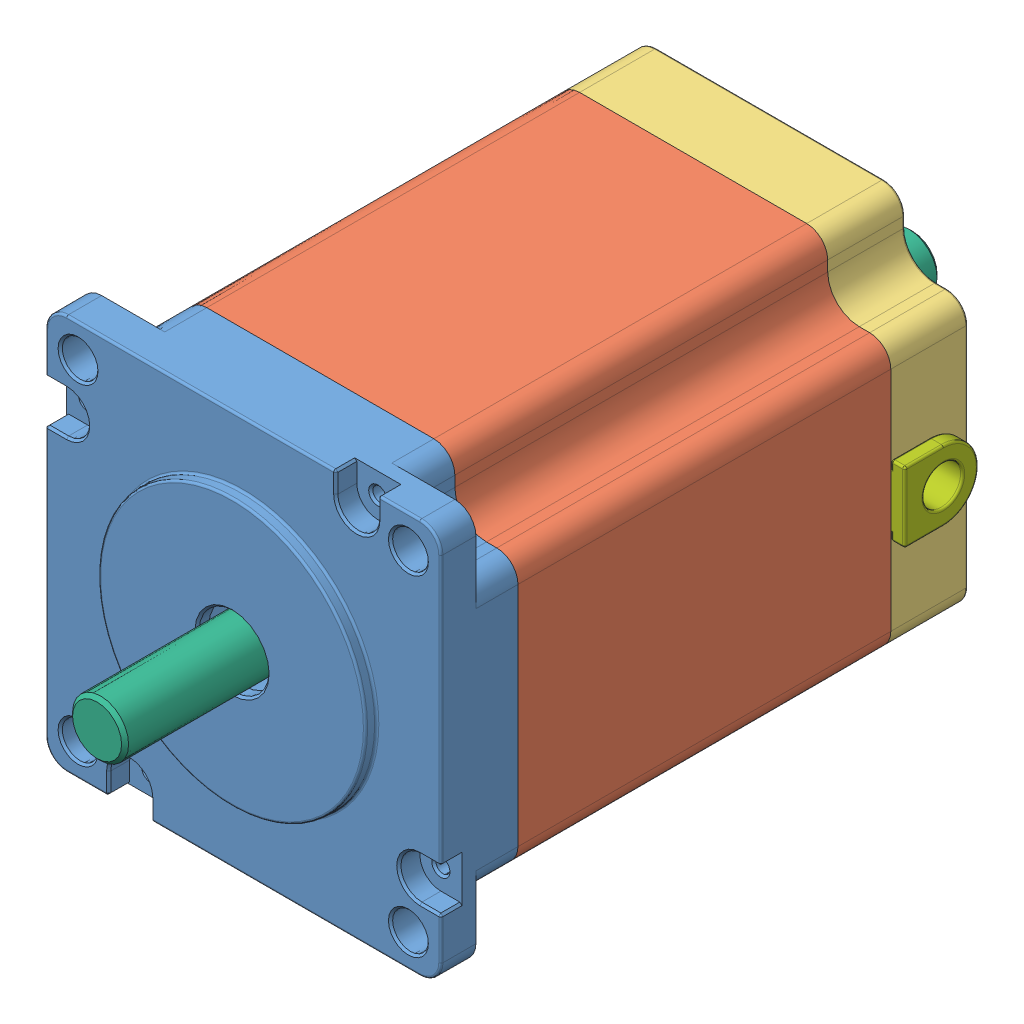
SolidWorks assembly Nema 23 Stepper Motor 57BYGH311D-12, configuration Default. Lengths in mm.
Overall size (58.4 56.4 135.95).
8 component instances, 8 part files, 16 mates.
Components (placement in the parent):
- 57BYGH311D-12-1-1: 57BYGH311D-12-1 [Default] at (-11.5747 12.4138 -2.3259) size (56.4 56.4 14.6)
- 57BYGH311D-12-2-1: 57BYGH311D-12-2 [Default] at (-11.5747 12.4138 -55.5259) size (56.4 56.4 53.2)
- 57BYGH311D-12-3-1: 57BYGH311D-12-3 [Default] at (-11.5747 12.4138 -55.5259) x (-1 0 0) z (0 0 -1) size (56.4 56.4 11)
- 57BYGH311D-12-4-2: 57BYGH311D-12-4 [Default] at (-11.5747 12.4138 -70.0259) size (36 36 15.4)
- 57BYGH311D-12-5-1: 57BYGH311D-12-5 [Default] at (-11.5747 12.4138 -70.5259) x (0.622515 0.782608 0) z (0 0 1) size (35.3 35.21 5)
- 57BYGH311D-12-6-1: 57BYGH311D-12-6 [Default] at (-11.5747 12.4138 -86.8259) size (8 8 116.35)
- 57BYGH311D-12-7-1: 57BYGH311D-12-7 [Default] at (15.4253 12.4138 -61.0259) x (1 0 0) z (0 1 0) size (6.2 10.5 12)
- coupler-1: coupler [Default] at (-11.5747 12.4138 19.5241) x (-0.005303 -0.999986 0) z (-0.999986 0.005303 0) size (26 29.6 26)
Mates (geometry in assembly coordinates):
- Coincident1: coincident: plane of 57BYGH311D-12-1-1 through (13.6253 37.6138 -2.3259) normal (0 0 -1); plane of 57BYGH311D-12-2-1 through (-35.2747 36.1138 -2.3259) normal (0 0 1)
- Coincident2: coincident: plane of 57BYGH311D-12-1-1 through (-36.7747 40.6138 8.6741) normal (0 1 0); plane of 57BYGH311D-12-2-1 through (4.6253 40.6138 -2.3259) normal (0 1 0)
- Coincident3: coincident: plane of 57BYGH311D-12-1-1 through (16.6253 37.6138 8.6741) normal (1 0 0); plane of 57BYGH311D-12-2-1 through (16.6253 28.6138 -2.3259) normal (1 0 0)
- Concentric1: concentric: cylinder of assembly; cylinder of assembly; cylinder of 57BYGH311D-12-3-1 through (-11.5747 12.4138 -65.5259) axis (0 0 1) radius 18; cylinder of 57BYGH311D-12-4-2 through (-11.5747 12.4138 -70.0259) axis (0 0 -1) radius 18
- Coincident4: coincident: plane of assembly; plane of assembly; plane of 57BYGH311D-12-3-1 through (-11.5747 12.4138 -65.5259) normal (0 0 1); plane of 57BYGH311D-12-4-2 through (-29.5747 12.4138 -65.5259) normal (0 0 -1)
- Coincident5: coincident: plane of assembly; plane of assembly; plane of 57BYGH311D-12-2-1 through (-35.2747 36.1138 -55.5259) normal (0 0 -1); plane of 57BYGH311D-12-3-1 through (12.1253 36.1138 -55.5259) normal (0 0 1)
- Coincident6: coincident: plane of assembly; plane of assembly; plane of 57BYGH311D-12-2-1 through (16.6253 28.6138 -2.3259) normal (1 0 0); plane of 57BYGH311D-12-3-1 through (16.6253 -3.7862 -66.5259) normal (1 0 0)
- Coincident7: coincident: plane of assembly; plane of assembly; plane of 57BYGH311D-12-2-1 through (4.6253 40.6138 -2.3259) normal (0 1 0); plane of 57BYGH311D-12-3-1 through (-27.7747 40.6138 -66.5259) normal (0 1 0)
- Coincident8: coincident: plane of assembly; plane of assembly; plane of 57BYGH311D-12-4-2 through (-29.5747 12.4138 -65.5259) normal (0 0 -1); plane of 57BYGH311D-12-5-1 through (-11.5747 12.4138 -65.5259) normal (0 0 1)
- Concentric2: concentric: cylinder of assembly; cylinder of assembly; cylinder of 57BYGH311D-12-4-2 through (-11.5747 12.4138 -70.0259) axis (0 0 -1) radius 11; cylinder of 57BYGH311D-12-5-1 through (-11.5747 12.4138 -65.5259) axis (0 0 -1) radius 11
- Concentric3: concentric: cylinder of 57BYGH311D-12-1-1 through (-11.5747 12.4138 8.6741) axis (0 0 -1) radius 5; cylinder of 57BYGH311D-12-6-1 through (-11.5747 12.4138 32.1741) axis (0 0 1) radius 4
- Concentric4: concentric: cylinder of assembly; cylinder of assembly; cylinder of 57BYGH311D-12-3-1 through (14.5253 12.4138 -61.0259) axis (1 0 0) radius 4; cylinder of 57BYGH311D-12-7-1 through (16.6253 12.4138 -61.0259) axis (-1 0 0) radius 4
- Coincident10: coincident: plane of assembly; plane of assembly; plane of 57BYGH311D-12-3-1 through (16.6253 -3.7862 -66.5259) normal (1 0 0); plane of 57BYGH311D-12-7-1 through (16.6253 12.4138 -61.0259) normal (-1 0 0)
- Distance1: distance = 19.25 mm: plane of 57BYGH311D-12-6-1 through (-20.6317 -9.3862 29.5241) normal (0 0 1); plane of 57BYGH311D-12-1-1 through (-11.5747 12.4138 10.2741) normal (0 0 1)
- Concentric1916: concentric: cylinder of assembly; cylinder of assembly; cylinder of 57BYGH311D-12-6-1 through (-11.5747 12.4138 32.1741) axis (0 0 1) radius 4; cylinder of coupler-1 through (-11.5747 12.4138 49.1241) axis (0 0 -1) radius 13
- Coincident4174: coincident: plane of assembly; plane of assembly; plane of 57BYGH311D-12-6-1 through (-20.6317 -9.3862 29.5241) normal (0 0 1); plane of coupler-1 through (-11.5747 12.4138 29.5241) normal (0 0 -1)
